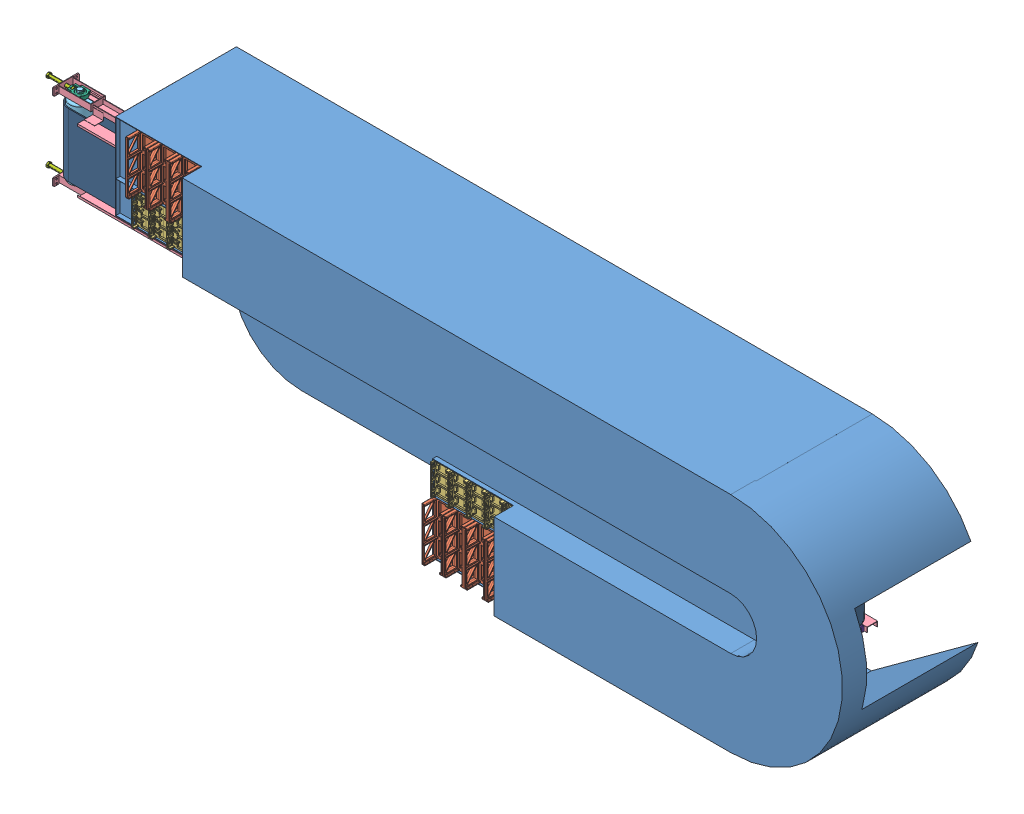
SolidWorks assembly Assieme3, configuration Default. Lengths in mm.
Overall size (8296.26 2114 1333.42).
43 component instances, 12 part files, 16 mates.
Components (placement in the parent):
- carico_vassoio-1: carico_vassoio [Default] at origin size (7062 2114 1330)
- vassoioX1_componibile-1: vassoioX1_componibile [Default] at (-3928 -510 1105) x (0 -1 0) z (0 0 1) size (500.32 200 150)
- vassoioX1_componibile-2: vassoioX1_componibile [Default] at (-6928 1093 1105) x (0 -1 0) z (0 0 1) size (500.32 200 150) (hidden)
- vassoioX2_componibile-1: vassoioX2_componibile [Default] at (-3942 -109.7 1105) x (0 -1 0) z (0 0 1) size (294.6 172 67)
- vassoioX2_componibile-2: vassoioX2_componibile [Default] at (-6942 689.3 1105) x (0 1 0) z (0 0 1) size (294.6 172 67) (hidden)
- vassoioX1_componibile-3: vassoioX1_componibile [Default] at (-6728 1093 1105) x (0 -1 0) z (0 0 1) size (500.32 200 150)
- vassoioX1_componibile-4: vassoioX1_componibile [Default] at (-6528 1093 1105) x (0 -1 0) z (0 0 1) size (500.32 200 150)
- vassoioX1_componibile-5: vassoioX1_componibile [Default] at (-6328 1093 1105) x (0 -1 0) z (0 0 1) size (500.32 200 150)
- vassoioX1_componibile-6: vassoioX1_componibile [Default] at (-6128 1093 1105) x (0 -1 0) z (0 0 1) size (500.32 200 150)
- vassoioX1_componibile-7: vassoioX1_componibile [Default] at (-5928 1093 1105) x (0 -1 0) z (0 0 1) size (500.32 200 150)
- vassoioX1_componibile-8: vassoioX1_componibile [Default] at (-3728 -510 1105) x (0 -1 0) z (0 0 1) size (500.32 200 150)
- vassoioX1_componibile-9: vassoioX1_componibile [Default] at (-3528 -510 1105) x (0 -1 0) z (0 0 1) size (500.32 200 150)
- vassoioX1_componibile-10: vassoioX1_componibile [Default] at (-3328 -510 1105) x (0 -1 0) z (0 0 1) size (500.32 200 150)
- vassoioX1_componibile-11: vassoioX1_componibile [Default] at (-3128 -510 1105) x (0 -1 0) z (0 0 1) size (500.32 200 150)
- vassoioX1_componibile-12: vassoioX1_componibile [Default] at (-2928 -510 1105) x (0 -1 0) z (0 0 1) size (500.32 200 150)
- vassoioX2_componibile-3: vassoioX2_componibile [Default] at (-3772 -109.7 1105) x (0 -1 0) z (0 0 1) size (294.6 172 67)
- vassoioX2_componibile-4: vassoioX2_componibile [Default] at (-3602 -109.7 1105) x (0 -1 0) z (0 0 1) size (294.6 172 67)
- vassoioX2_componibile-5: vassoioX2_componibile [Default] at (-3432 -109.7 1105) x (0 -1 0) z (0 0 1) size (294.6 172 67)
- vassoioX2_componibile-6: vassoioX2_componibile [Default] at (-3262 -109.7 1105) x (0 -1 0) z (0 0 1) size (294.6 172 67)
- vassoioX2_componibile-7: vassoioX2_componibile [Default] at (-3092 -109.7 1105) x (0 -1 0) z (0 0 1) size (294.6 172 67)
- vassoioX2_componibile-8: vassoioX2_componibile [Default] at (-6772 689.3 1105) x (0 1 0) z (0 0 1) size (294.6 172 67)
- vassoioX2_componibile-9: vassoioX2_componibile [Default] at (-6602 689.3 1105) x (0 1 0) z (0 0 1) size (294.6 172 67)
- vassoioX2_componibile-10: vassoioX2_componibile [Default] at (-6432 689.3 1105) x (0 1 0) z (0 0 1) size (294.6 172 67)
- vassoioX2_componibile-11: vassoioX2_componibile [Default] at (-6262 689.3 1105) x (0 1 0) z (0 0 1) size (294.6 172 67)
- vassoioX2_componibile-12: vassoioX2_componibile [Default] at (-6092 689.3 1105) x (0 1 0) z (0 0 1) size (294.6 172 67)
- Assieme4-1: Assieme4 [Default] at (-7592.755 789.8405 -0.2909) x (1 0.000489 -0.000207) z (0.000489 -1 0.000382) size (7694.54 747.46 815.72)
  - nastrodx-1: nastrodx [Default] at (-736.9413 -3228.8791 379.4071) size (7694.54 747.46 815.72)
    - C-channel -b-up-2: C-channel -b-up [Default<As Machined>] at (4036.4781 3775.6231 338.4141) x (0.000207 -1 -0.000382) z (-1 -0.000206 -0.000489) size (1248 810 7547.03)
    - roller-belt-Motor-up-1: roller-belt-Motor-up [Default] at (7631.6404 3780.4929 5.1727) x (0.000489 0.000382 -1) z (1 0 0.000489) size (812 200 200)
    - Uct 209-up-1: Uct 209-up [Default] at (366.4634 3774.8539 367.6204) x (1 0.000206 0.000489) z (-0.000489 -0.000382 1) size (144 117 54.7)
    - Extender-screw-up-1: Extender-screw-up [Default] at (302.9634 3774.8408 367.5894) x (0.000489 0 -1) z (-1 -0.000206 -0.000489) size (46.02 42.15 250)
    - Bearing-b_P209_45-up-1: Bearing-b_P209_45-up [Default] at (7631.4747 3726.3547 367.152) x (1 0.000206 0.000489) z (-0.000489 -0.000382 1) size (190 108 62)
    - upper-roller-inside-up-1: upper-roller-inside-up [Default] at (6502.8061 3649.373 4.571) x (1 0 0.000489) z (-0.000489 -0.000382 1) size (50 50 810)
    - Bearing-b_P209_45-up-2: Bearing-b_P209_45-up [Default] at (7631.8285 3726.6312 -356.8478) x (-1 -0.000206 -0.000489) z (0.000489 0.000382 -1) size (190 108 62)
    - Uct 209-up-2: Uct 209-up [Default] at (366.8211 3775.1334 -364.3794) x (1 0.000206 0.000489) z (0.000489 0.000382 -1) size (144 117 54.7)
    - Extender-screw-up-2: Extender-screw-up [Default] at (303.3211 3775.1203 -364.4105) x (0.000489 0.000764 -1) z (-1 -0.000206 -0.000489) size (46.02 42.15 250)
    - upper-roller-inside-up-2: upper-roller-inside-up [Default] at (4122.8064 3648.8818 3.4078) x (1 0 0.000489) z (-0.000489 -0.000382 1) size (50 50 810)
    - upper-roller-inside-up-3: upper-roller-inside-up [Default] at (1742.8067 3648.3906 2.2446) x (1 0 0.000489) z (-0.000489 -0.000382 1) size (50 50 810)
    - Belt-1: Belt [Default] at (4036.6418 3775.751 3.4142) x (-0.000207 1 0.000382) z (0.000489 0.000382 -1) size (228 7489 600)
    - roller-upper-2: roller-upper [Default] at (5639.6653 3862.5818 4.2307) x (1 0 0.000489) z (-0.000489 -0.000382 1) size (29 29 810)
    - UCP-205-1: UCP-205 [Default] at (5639.4923 3862.4467 358.2306) x (0.000489 0.000382 -1) z (1 0 0.000489) size (38.7 70 140)
    - UCP-205-2: UCP-205 [Default] at (5639.8383 3862.717 -349.7693) x (0.000489 0.000382 -1) z (1 0.000206 0.000489) size (38.7 70 140)
    - roller-belt-Motor-up-2: roller-belt-Motor-up [Default] at (366.6414 3778.9936 1.622) x (0.000489 0.000382 -1) z (1 0 0.000489) size (812 200 200)
Mates (geometry in assembly coordinates):
- Coincidente1: coincident anti-aligned: plane of carico_vassoio-1 through (-4028 42 1100) normal (1 0 0); plane of vassoioX1_componibile-1 through (-4028 -260 1108) normal (-1 0 0)
- Coincidente2: coincident anti-aligned: plane of carico_vassoio-1 through (-1028 292 1105) normal (0 0 1); plane of vassoioX1_componibile-1 through (-3928 -510 1105) normal (0 0 -1)
- Coincidente3: coincident anti-aligned: plane of carico_vassoio-1 through (-4028 -760 1100) normal (0 1 0); plane of vassoioX1_componibile-1 through (-3828 -760 1108) normal (0 -1 0)
- Coincidente4: coincident anti-aligned: plane of carico_vassoio-1 through (-7028 1344 1100) normal (1 0 0); plane of vassoioX1_componibile-2 through (-7028 1343 1108) normal (-1 0 0)
- Coincidente5: coincident anti-aligned: plane of carico_vassoio-1 through (-1028 843 7788.0418) normal (0 1 0); plane of vassoioX1_componibile-2 through (-6828 843 1108) normal (0 -1 0)
- Coincidente6: coincident anti-aligned: plane of carico_vassoio-1 through (-1028 292 1105) normal (0 0 1); plane of vassoioX1_componibile-2 through (-6928 1093 1105) normal (0 0 -1)
- Coincidente7: coincident anti-aligned: plane of carico_vassoio-1 through (-7028 1344 1100) normal (1 0 0); plane of vassoioX2_componibile-2 through (-7028 542 1115) normal (-1 0 0)
- Coincidente8: coincident anti-aligned: plane of carico_vassoio-1 through (-7028 542 1100) normal (0 1 0); plane of vassoioX2_componibile-2 through (-7028 542 1115) normal (0 -1 0)
- Coincidente9: coincident anti-aligned: plane of carico_vassoio-1 through (-1028 292 1105) normal (0 0 1); plane of vassoioX2_componibile-2 through (-6942 689.3 1105) normal (0 0 -1)
- Coincidente10: coincident anti-aligned: plane of carico_vassoio-1 through (-1028 -257 7788.0418) normal (0 1 0); plane of vassoioX2_componibile-1 through (-3856 -257 1115) normal (0 -1 0)
- Coincidente11: coincident anti-aligned: plane of carico_vassoio-1 through (-4028 42 1100) normal (1 0 0); plane of vassoioX2_componibile-1 through (-4028 37.6 1115) normal (-1 0 0)
- Coincidente12: coordinate: point of carico_vassoio-1
- Coincidente13: coincident anti-aligned: plane of carico_vassoio-1 through (-1028 292 1105) normal (0 0 1); plane of vassoioX2_componibile-1 through (-3942 -109.7 1105) normal (0 0 -1)
- Parallelo1: parallel anti-aligned: plane of carico_vassoio-1 through (-1028 292 1100) normal (0 0 -1); plane of Assieme4-1/nastrodx-1/Belt-1 through (-7962.755 708.8405 660.0455) normal (0 0 1)
- Coincidente15: coincident anti-aligned: plane of carico_vassoio-1 through (-7028 814.8405 0) normal (0 -1 0); plane of Assieme4-1/nastrodx-1/roller-belt-Motor-up-1 through (-697.755 814.8405 550.0455) normal (0 1 0)
- Coincidente16: coincident: plane of carico_vassoio-1 through (0 0 0) normal (0 0 -1); point of Assieme4-1/nastrodx-1/C-channel -b-up-2
